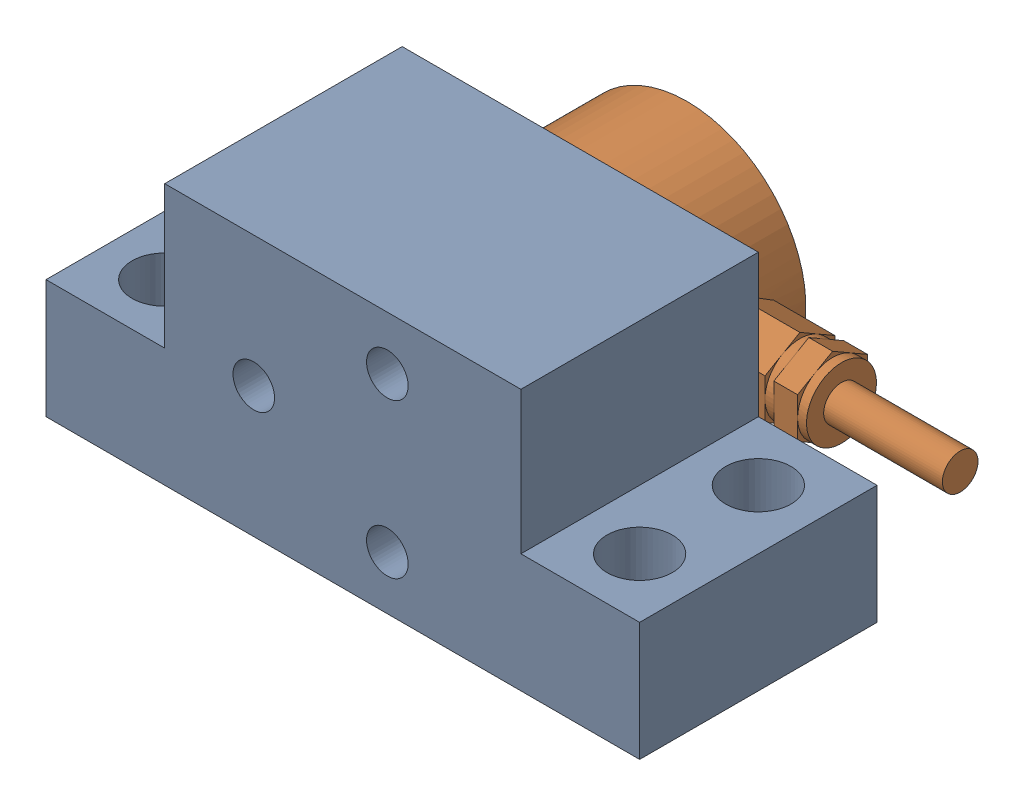
SolidWorks assembly Aynalamaloadcel yatay montaj-2, configuration Default. Lengths in mm.
Overall size (53.5 22 31).
2 component instances, 2 part files, 0 mates.
Components (placement in the parent):
- AynalamaLoadcell yatay ayak-1: AynalamaLoadcell yatay ayak [Default] at origin size (50 22 20)
- AynalamaMini_Loadcell-1: AynalamaMini_Loadcell [Default] at (0 11 -19) x (-1 0 0) z (0 -1 0) size (38.5 12 20)
